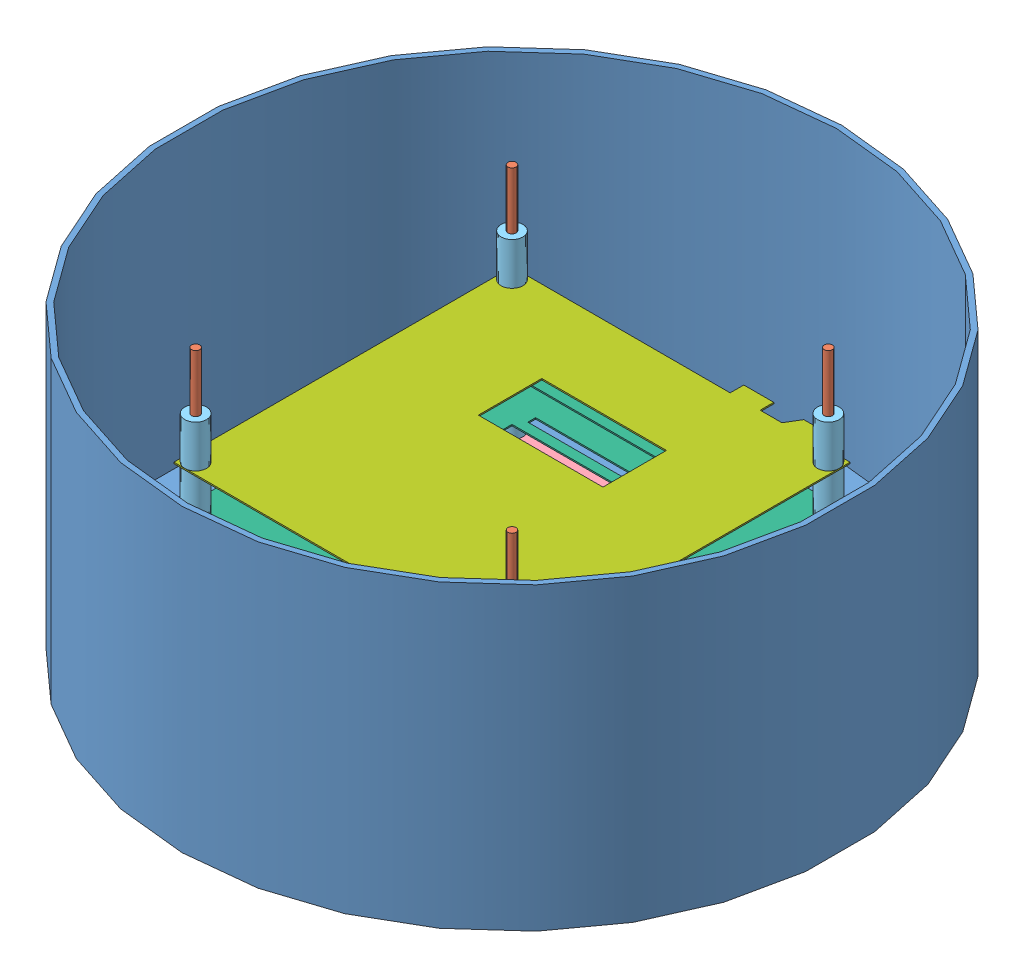
SolidWorks assembly уровень жидкости, configuration По умолчанию. Lengths in mm.
Overall size (242 110 242).
29 component instances, 7 part files, 55 mates.
Components (placement in the parent):
- стакан-1: стакан [По умолчанию] at (139.6601 139.8361 139.6601) size (242 110 242)
- палка-1: палка [По умолчанию] at (81.6601 139.8361 81.6601) size (3 100 3)
- палка-2: палка [По умолчанию] at (81.6601 139.8361 197.6601) size (3 100 3)
- палка-3: палка [По умолчанию] at (197.6601 139.8361 81.6601) size (3 100 3)
- палка-4: палка [По умолчанию] at (197.6601 139.8361 197.6601) size (3 100 3)
- гайка-1: гайка [По умолчанию] at (77.5601 152.8661 85.7601) size (8.2 2 8.2)
- гайка-2: гайка [По умолчанию] at (193.5601 152.8661 85.7601) size (8.2 2 8.2)
- гайка-3: гайка [По умолчанию] at (193.5601 152.8661 201.7601) size (8.2 2 8.2)
- гайка-4: гайка [По умолчанию] at (77.5601 152.8661 201.7601) size (8.2 2 8.2)
- джем2 низ-1: джем2 низ [По умолчанию] at (77.6601 154.8661 201.6601) size (124 0.5 124)
- столбик15_5мм-1: столбик15_5мм [По умолчанию] at (81.6601 155.3295 81.6601) size (8 15.5 8)
- столбик15_5мм-2: столбик15_5мм [По умолчанию] at (81.6601 155.3295 197.6601) size (8 15.5 8)
- столбик15_5мм-3: столбик15_5мм [По умолчанию] at (197.6601 155.3295 197.6601) size (8 15.5 8)
- столбик15_5мм-4: столбик15_5мм [По умолчанию] at (197.6601 155.3295 81.6601) size (8 15.5 8)
- кольцо-1: кольцо [По умолчанию] at (77.6601 170.8661 201.6601) size (124 0.5 124)
- столбик15_5мм-5: столбик15_5мм [По умолчанию] at (81.6601 171.3295 197.6601) size (8 15.5 8)
- столбик15_5мм-6: столбик15_5мм [По умолчанию] at (81.6601 171.3295 81.6601) size (8 15.5 8)
- столбик15_5мм-7: столбик15_5мм [По умолчанию] at (197.6601 171.3295 81.6601) size (8 15.5 8)
- столбик15_5мм-8: столбик15_5мм [По умолчанию] at (197.6601 171.3295 197.6601) size (8 15.5 8)
- кольцо-2: кольцо [По умолчанию] at (77.6601 186.8661 201.6601) size (124 0.5 124)
- столбик15_5мм-9: столбик15_5мм [По умолчанию] at (81.6601 187.3295 81.6601) size (8 15.5 8)
- столбик15_5мм-10: столбик15_5мм [По умолчанию] at (197.6601 187.3295 81.6601) size (8 15.5 8)
- столбик15_5мм-11: столбик15_5мм [По умолчанию] at (197.6601 187.3295 197.6601) size (8 15.5 8)
- столбик15_5мм-12: столбик15_5мм [По умолчанию] at (81.6601 187.3295 197.6601) size (8 15.5 8)
- джем1-1: джем1 [По умолчанию] at (77.6601 202.8661 201.6601) size (124 0.5 129)
- столбик15_5мм-13: столбик15_5мм [По умолчанию] at (81.6601 203.3295 81.6601) size (8 15.5 8)
- столбик15_5мм-14: столбик15_5мм [По умолчанию] at (197.6601 203.3295 81.6601) size (8 15.5 8)
- столбик15_5мм-15: столбик15_5мм [По умолчанию] at (197.6601 203.3295 197.6601) size (8 15.5 8)
- столбик15_5мм-16: столбик15_5мм [По умолчанию] at (81.6601 203.3295 197.6601) size (8 15.5 8)
Mates (geometry in assembly coordinates):
- Концентричный1: concentric aligned: circle of стакан-1; circle of палка-4
- Совпадение4: coincident anti-aligned: plane of стакан-1 through (139.6601 139.8361 139.6601) normal (0 -1 0); circle of палка-4
- Совпадение5: coincident aligned: circle of стакан-1; circle of палка-3
- Совпадение6: coincident aligned: circle of стакан-1; circle of палка-1
- Совпадение7: coincident aligned: circle of стакан-1; circle of палка-2
- Концентричный7: concentric anti-aligned: cylinder of палка-3 through (197.6601 239.8361 81.6601) axis (0 -1 0) radius 1.5; circle of гайка-2
- Совпадение11: coincident aligned: circle of стакан-1; plane of гайка-2 through (193.5601 152.8661 85.7601) normal (0 -1 0)
- Концентричный8: concentric anti-aligned: cylinder of палка-1 through (81.6601 239.8361 81.6601) axis (0 -1 0) radius 1.5; circle of гайка-1
- Концентричный9: concentric anti-aligned: cylinder of палка-2 through (81.6601 239.8361 197.6601) axis (0 -1 0) radius 1.5; circle of гайка-4
- Концентричный10: concentric anti-aligned: cylinder of палка-4 through (197.6601 239.8361 197.6601) axis (0 -1 0) radius 1.5; circle of гайка-3
- Совпадение12: coincident anti-aligned: plane of стакан-1 through (139.6601 152.8661 139.6601) normal (0 1 0); plane of гайка-3 through (193.5601 152.8661 201.7601) normal (0 -1 0)
- Совпадение13: coincident aligned: circle of стакан-1; plane of гайка-4 through (77.5601 152.8661 201.7601) normal (0 -1 0)
- Совпадение14: coincident aligned: circle of стакан-1; plane of гайка-1 through (77.5601 152.8661 85.7601) normal (0 -1 0)
- Совпадение15: coincident anti-aligned: plane of гайка-2 through (193.5601 154.8661 85.7601) normal (0 1 0); plane of джем2 низ-1 through (77.6601 154.8661 201.6601) normal (0 -1 0)
- Концентричный11: concentric anti-aligned: cylinder of палка-3 through (197.6601 239.8361 81.6601) axis (0 -1 0) radius 1.5; circle of джем2 низ-1
- Концентричный12: concentric anti-aligned: cylinder of палка-4 through (197.6601 239.8361 197.6601) axis (0 -1 0) radius 1.5; circle of джем2 низ-1
- Концентричный13: concentric aligned: cylinder of палка-3 through (197.6601 239.8361 81.6601) axis (0 -1 0) radius 1.5; circle of столбик15_5мм-4
- Концентричный14: concentric aligned: cylinder of палка-1 through (81.6601 239.8361 81.6601) axis (0 -1 0) radius 1.5; circle of столбик15_5мм-1
- Концентричный15: concentric aligned: cylinder of палка-2 through (81.6601 239.8361 197.6601) axis (0 -1 0) radius 1.5; cylinder of столбик15_5мм-2 through (81.6601 155.3295 197.6601) axis (0 -1 0) radius 1.5
- Совпадение16: coincident aligned: cylinder of палка-4 through (197.6601 239.8361 197.6601) axis (0 -1 0) radius 1.5; circle of столбик15_5мм-3
- Совпадение17: coincident anti-aligned: plane of джем2 низ-1 through (77.6601 155.3661 201.6601) normal (0 1 0); plane of столбик15_5мм-3 through (201.6601 155.3661 197.6601) normal (0 -1 0)
- Совпадение18: coincident anti-aligned: plane of джем2 низ-1 through (77.6601 155.3661 201.6601) normal (0 1 0); circle of столбик15_5мм-4
- Совпадение19: coincident anti-aligned: plane of джем2 низ-1 through (77.6601 155.3661 201.6601) normal (0 1 0); circle of столбик15_5мм-1
- Совпадение20: coincident anti-aligned: plane of джем2 низ-1 through (77.6601 155.3661 201.6601) normal (0 1 0); circle of столбик15_5мм-2
- Совпадение21: coincident anti-aligned: plane of столбик15_5мм-2 through (83.1601 170.8661 197.6601) normal (0 1 0); plane of кольцо-1 through (77.6601 170.8661 201.6601) normal (0 -1 0)
- Концентричный16: concentric anti-aligned: cylinder of палка-1 through (81.6601 239.8361 81.6601) axis (0 -1 0) radius 1.5; circle of кольцо-1
- Концентричный17: concentric aligned: cylinder of палка-4 through (197.6601 239.8361 197.6601) axis (0 -1 0) radius 1.5; circle of столбик15_5мм-8
- Концентричный18: concentric aligned: cylinder of палка-2 through (81.6601 239.8361 197.6601) axis (0 -1 0) radius 1.5; circle of столбик15_5мм-5
- Концентричный19: concentric aligned: cylinder of палка-1 through (81.6601 239.8361 81.6601) axis (0 -1 0) radius 1.5; circle of столбик15_5мм-6
- Концентричный20: concentric aligned: cylinder of палка-3 through (197.6601 239.8361 81.6601) axis (0 -1 0) radius 1.5; circle of столбик15_5мм-7
- Совпадение22: coincident anti-aligned: plane of кольцо-1 through (77.6601 171.3661 201.6601) normal (0 1 0); circle of столбик15_5мм-7
- Совпадение23: coincident anti-aligned: plane of кольцо-1 through (77.6601 171.3661 201.6601) normal (0 1 0); circle of столбик15_5мм-5
- Совпадение24: coincident anti-aligned: plane of кольцо-1 through (77.6601 171.3661 201.6601) normal (0 1 0); circle of столбик15_5мм-8
- Совпадение25: coincident anti-aligned: plane of кольцо-1 through (77.6601 171.3661 201.6601) normal (0 1 0); circle of столбик15_5мм-6
- Совпадение26: coincident anti-aligned: plane of столбик15_5мм-6 through (83.1601 186.8661 81.6601) normal (0 1 0); plane of кольцо-2 through (77.6601 186.8661 201.6601) normal (0 -1 0)
- Концентричный21: concentric anti-aligned: cylinder of палка-1 through (81.6601 239.8361 81.6601) axis (0 -1 0) radius 1.5; circle of кольцо-2
- Совпадение27: coincident anti-aligned: plane of кольцо-2 through (77.6601 187.3661 201.6601) normal (0 1 0); circle of столбик15_5мм-11
- Совпадение29: coincident anti-aligned: plane of кольцо-2 through (77.6601 187.3661 201.6601) normal (0 1 0); circle of столбик15_5мм-10
- Совпадение31: coincident anti-aligned: plane of кольцо-2 through (77.6601 187.3661 201.6601) normal (0 1 0); circle of столбик15_5мм-12
- Совпадение32: coincident anti-aligned: plane of кольцо-2 through (77.6601 187.3661 201.6601) normal (0 1 0); circle of столбик15_5мм-9
- Концентричный22: concentric aligned: cylinder of палка-1 through (81.6601 239.8361 81.6601) axis (0 -1 0) radius 1.5; circle of столбик15_5мм-9
- Концентричный23: concentric aligned: cylinder of палка-2 through (81.6601 239.8361 197.6601) axis (0 -1 0) radius 1.5; circle of столбик15_5мм-12
- Концентричный24: concentric aligned: cylinder of палка-4 through (197.6601 239.8361 197.6601) axis (0 -1 0) radius 1.5; circle of столбик15_5мм-11
- Концентричный25: concentric aligned: cylinder of палка-3 through (197.6601 239.8361 81.6601) axis (0 -1 0) radius 1.5; circle of столбик15_5мм-10
- Совпадение33: coincident anti-aligned: plane of столбик15_5мм-9 through (83.1601 202.8661 81.6601) normal (0 1 0); plane of джем1-1 through (77.6601 202.8661 201.6601) normal (0 -1 0)
- Концентричный26: concentric anti-aligned: cylinder of палка-1 through (81.6601 239.8361 81.6601) axis (0 -1 0) radius 1.5; circle of джем1-1
- Концентричный27: concentric anti-aligned: cylinder of палка-2 through (81.6601 239.8361 197.6601) axis (0 -1 0) radius 1.5; circle of джем1-1
- Совпадение34: coincident anti-aligned: plane of джем1-1 through (77.6601 203.3661 201.6601) normal (0 1 0); circle of столбик15_5мм-16
- Совпадение35: coincident anti-aligned: plane of джем1-1 through (77.6601 203.3661 201.6601) normal (0 1 0); circle of столбик15_5мм-13
- Совпадение36: coincident anti-aligned: plane of джем1-1 through (77.6601 203.3661 201.6601) normal (0 1 0); circle of столбик15_5мм-15
- Совпадение37: coincident anti-aligned: plane of джем1-1 through (77.6601 203.3661 201.6601) normal (0 1 0); circle of столбик15_5мм-14
- Концентричный28: concentric aligned: cylinder of палка-3 through (197.6601 239.8361 81.6601) axis (0 -1 0) radius 1.5; circle of столбик15_5мм-14
- Концентричный29: concentric aligned: cylinder of палка-1 through (81.6601 239.8361 81.6601) axis (0 -1 0) radius 1.5; circle of столбик15_5мм-13
- Концентричный30: concentric aligned: cylinder of палка-2 through (81.6601 239.8361 197.6601) axis (0 -1 0) radius 1.5; circle of столбик15_5мм-16
- Концентричный31: concentric aligned: cylinder of палка-4 through (197.6601 239.8361 197.6601) axis (0 -1 0) radius 1.5; circle of столбик15_5мм-15
